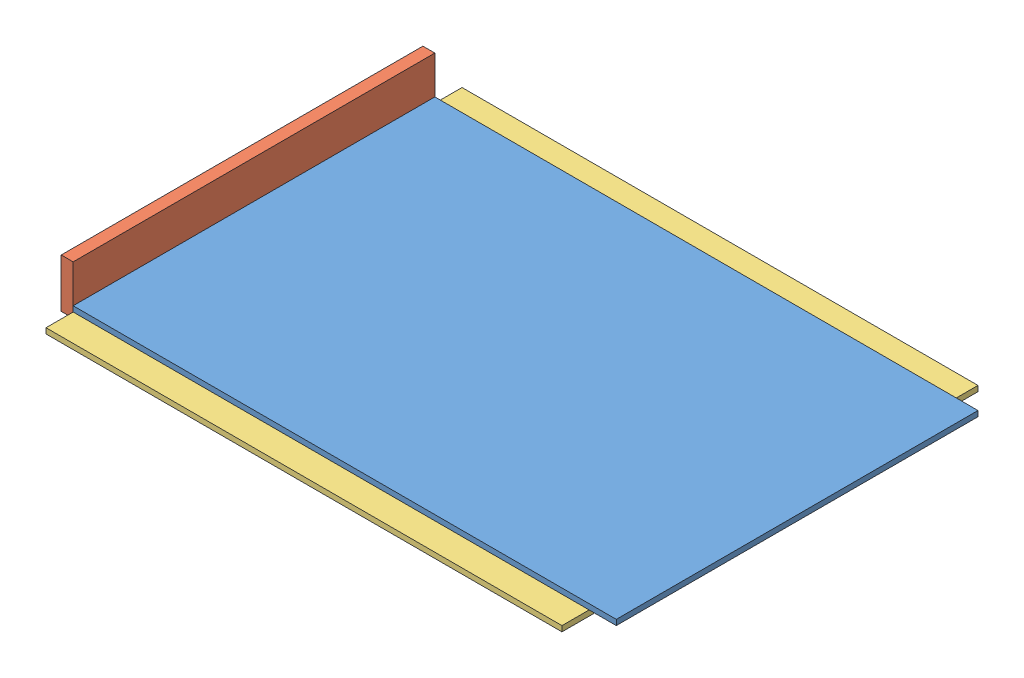
SolidWorks assembly Assemblage3, configuration Default. Lengths in mm.
Overall size (1022 90 766).
5 component instances, 4 part files, 12 mates.
Components (placement in the parent):
- planche_1000x666x10-1: planche_1000x666x10 [Default] at (-672.8072 89.9278 359.6954) size (1000 10 666)
- planche_666x90x22-1: planche_666x90x22 [Default] at (-694.8072 79.9278 359.6954) x (0 0 -1) z (1 0 0) size (666 90 22)
- planche_950x100x10-1: planche_950x100x10 [Default] at (-672.8072 79.9278 409.6954) size (950 10 100)
- planche_950x100x10-2: planche_950x100x10 [Default] at (-672.8072 79.9278 -256.3046) size (950 10 100)
- planche_566x100x10-1: planche_566x100x10 [Default] at (-672.8072 79.9278 -256.3046) x (0 0 1) z (-1 0 0) size (566 10 100)
Mates (geometry in assembly coordinates):
- Coïncidente1: coincident anti-aligned: plane of planche_1000x666x10-1 through (-672.8072 99.9278 359.6954) normal (-1 0 0); plane of planche_666x90x22-1 through (-672.8072 169.9278 359.6954) normal (1 0 0)
- Coïncidente2: coincident aligned: plane of planche_1000x666x10-1 through (-672.8072 99.9278 359.6954) normal (0 0 1); plane of planche_666x90x22-1 through (-672.8072 79.9278 359.6954) normal (0 0 1)
- Coïncidente3: coincident anti-aligned: plane of planche_1000x666x10-1 through (-672.8072 89.9278 -306.3046) normal (0 -1 0); plane of planche_950x100x10-1 through (-672.8072 89.9278 309.6954) normal (0 1 0)
- Coïncidente4: coincident aligned: plane of planche_1000x666x10-1 through (-672.8072 99.9278 359.6954) normal (-1 0 0); plane of planche_950x100x10-1 through (-672.8072 89.9278 409.6954) normal (-1 0 0)
- Coïncidente5: coincident aligned: plane of planche_666x90x22-1 through (-672.8072 79.9278 359.6954) normal (0 -1 0); plane of planche_950x100x10-1 through (-672.8072 79.9278 309.6954) normal (0 -1 0)
- Distance1: distance = 50 mm aligned: plane of planche_950x100x10-1 through (-672.8072 89.9278 409.6954) normal (0 0 1); plane of planche_1000x666x10-1 through (-672.8072 99.9278 359.6954) normal (0 0 1)
- Coïncidente7: coincident anti-aligned: plane of planche_1000x666x10-1 through (-672.8072 89.9278 -306.3046) normal (0 -1 0); plane of planche_950x100x10-2 through (-672.8072 89.9278 -356.3046) normal (0 1 0)
- Coïncidente8: coincident anti-aligned: plane of planche_666x90x22-1 through (-672.8072 169.9278 359.6954) normal (1 0 0); plane of planche_950x100x10-2 through (-672.8072 89.9278 -256.3046) normal (-1 0 0)
- Distance2: distance = 50 mm anti-aligned: plane of planche_950x100x10-2 through (-672.8072 89.9278 -256.3046) normal (0 0 1); plane of planche_1000x666x10-1 through (-672.8072 99.9278 -306.3046) normal (0 0 -1)
- Coïncidente10: coincident anti-aligned: plane of planche_950x100x10-1 through (-672.8072 89.9278 309.6954) normal (0 0 -1); plane of ? through (-77.5535 89.9278 309.6954) normal (0 0 1)
- Coïncidente11: coincident anti-aligned: plane of planche_1000x666x10-1 through (-672.8072 89.9278 -306.3046) normal (0 -1 0); plane of ? through (22.4465 89.9278 -256.3046) normal (0 1 0)
- Coïncidente12: coincident anti-aligned: plane of planche_666x90x22-1 through (-672.8072 169.9278 359.6954) normal (1 0 0); plane of ? through (-77.5535 89.9278 -256.3046) normal (-1 0 0)
